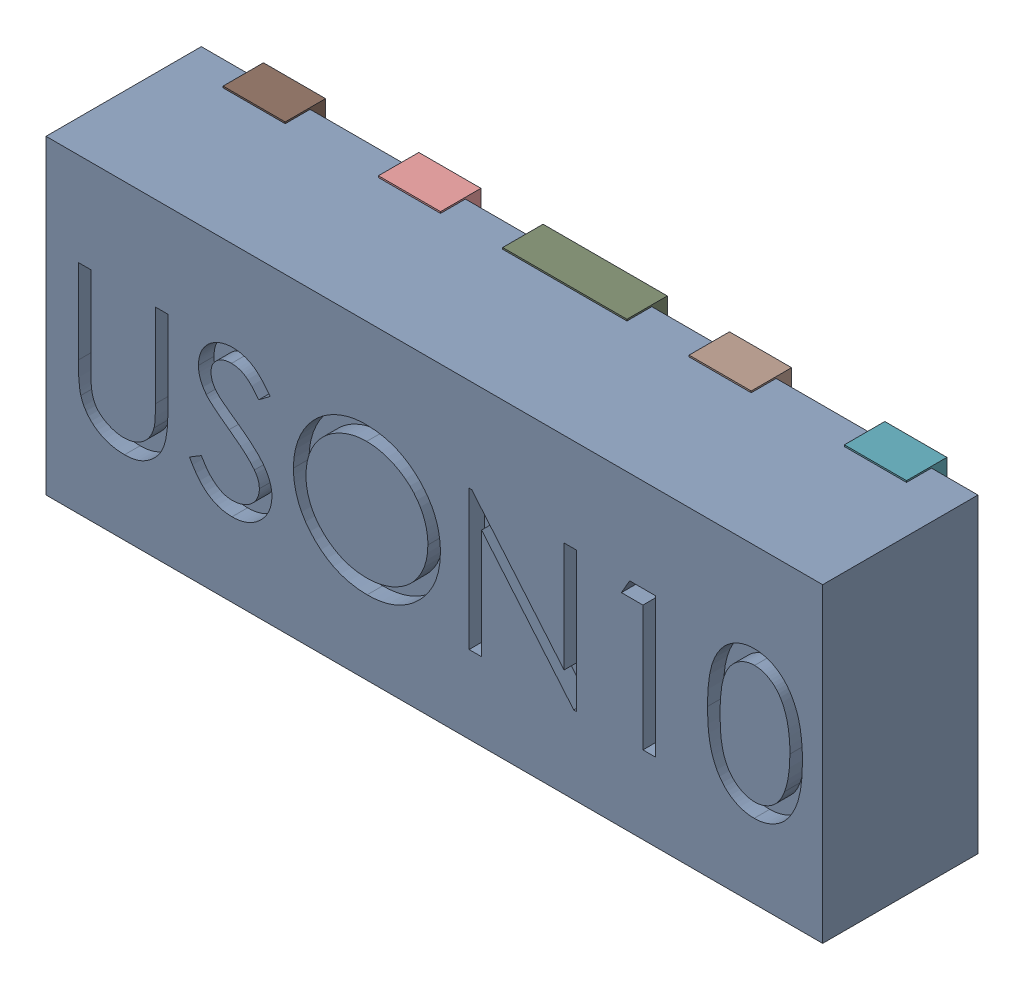
SolidWorks assembly D10, configuration Défaut. Lengths in mm.
Overall size (2.5 1.01 0.55).
12 component instances, 5 part files, 0 mates.
Components (placement in the parent):
- UDFN10-1: UDFN10 [Défaut] at (38.7923 -33.7093 -0.9099) x (1 0 0) z (0 -1 0) size (2.5 0.55 1.01)
  - User Library-UDFN10_Body-1: User Library-UDFN10_Body [Défaut] at (1.0785 0.9721 1.8983) size (2.5 0.5 1)
  - User Library-UDFN10_Pin1-1: User Library-UDFN10_Pin1 [Défaut] at (0.0785 1.0521 2.2208) x (0 0 -1) z (-1 0 0) size (0.37 0.13 0.2)
  - User Library-UDFN10_Pin2-1: User Library-UDFN10_Pin2 [Défaut] at (0.5785 1.0521 2.2208) x (0 0 1) z (1 0 0) size (0.37 0.13 0.2)
  - User Library-UDFN10_Pin4-1: User Library-UDFN10_Pin4 [Défaut] at (1.0785 0.9221 2.2208) x (0 0 1) z (-1 0 0) size (0.49 0.13 0.4)
  - User Library-UDFN10_Pin2-2: User Library-UDFN10_Pin2 [Défaut] at (1.5785 0.9221 2.2208) x (0 0 1) z (-1 0 0) size (0.37 0.13 0.2)
  - User Library-UDFN10_Pin2-3: User Library-UDFN10_Pin2 [Défaut] at (2.0785 0.9221 2.2208) x (0 0 1) z (-1 0 0) size (0.37 0.13 0.2)
  - User Library-UDFN10_Pin2-4: User Library-UDFN10_Pin2 [Défaut] at (2.0785 0.9221 1.5758) x (0 0 -1) z (1 0 0) size (0.37 0.13 0.2)
  - User Library-UDFN10_Pin2-5: User Library-UDFN10_Pin2 [Défaut] at (1.5785 0.9221 1.5758) x (0 0 -1) z (1 0 0) size (0.37 0.13 0.2)
  - User Library-UDFN10_Pin3-1: User Library-UDFN10_Pin3 [Défaut] at (1.0785 0.9221 1.5758) x (0 0 1) z (-1 0 0) size (0.37 0.13 0.4)
  - User Library-UDFN10_Pin2-6: User Library-UDFN10_Pin2 [Défaut] at (0.5785 0.9221 1.5758) x (0 0 -1) z (1 0 0) size (0.37 0.13 0.2)
  - User Library-UDFN10_Pin2-7: User Library-UDFN10_Pin2 [Défaut] at (0.0785 0.9221 1.5758) x (0 0 -1) z (1 0 0) size (0.37 0.13 0.2)
